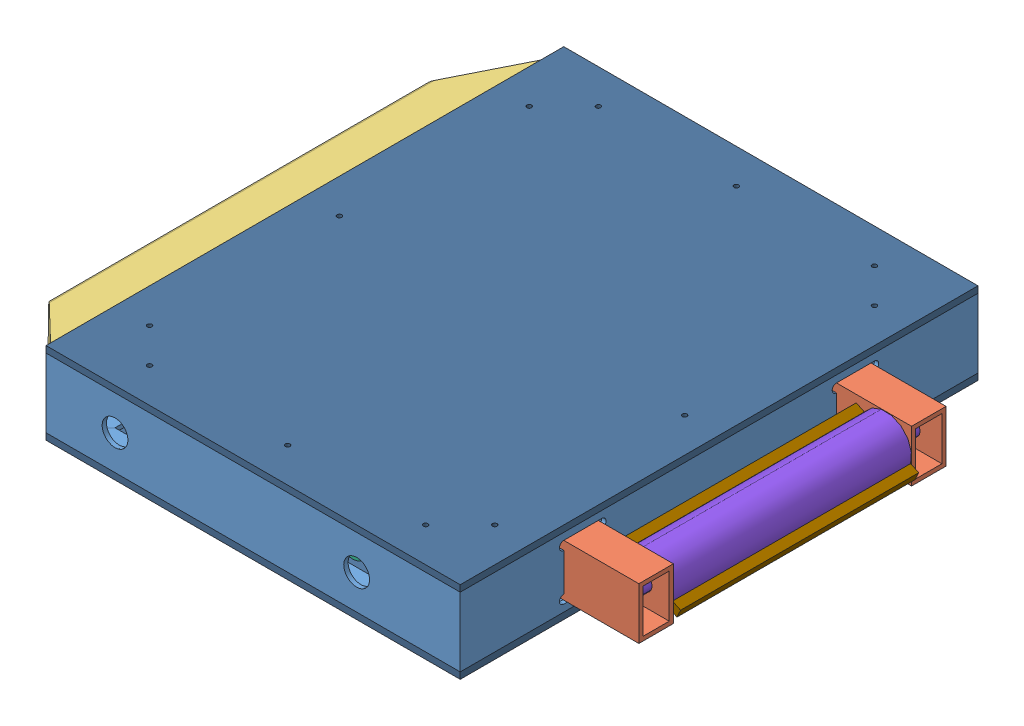
SolidWorks assembly Robot, configuration Default. Lengths in mm.
Overall size (423.92 71.11 381).
28 component instances, 11 part files, 15 mates.
Components (placement in the parent):
- Frame-1: Frame [Default] at (141.475 35.5407 10.1668) size (411.9 66.35 381)
  - Frame C-Channel-1: Frame C-Channel [Front] at (140.3478 189.2176 116.1664) x (0 1 0) z (0 0 1) size (50.8 25.4 381)
  - Frame C-Channel-2: Frame C-Channel [Back] at (-164.4522 189.2176 116.1664) x (0 -1 0) z (0 0 1) size (50.8 25.4 381)
  - Frame C-Channel-3: Frame C-Channel [Side] at (140.3478 189.2176 116.1664) x (0 -1 0) z (-1 0 0) size (50.8 25.4 304.8)
  - Frame C-Channel-4: Frame C-Channel [Side] at (140.3478 189.2176 497.1664) x (0 1 0) z (-1 0 0) size (50.8 25.4 304.8)
  - Roller Arm-1: Roller Arm [Motor] at (-161.2772 189.2176 206.3364) x (1 0 0) z (0 0 -1) size (355.6 38.1 25.4)
  - Roller Arm-2: Roller Arm [Default] at (-161.2772 189.2176 406.9964) size (355.6 38.1 25.4)
  - Rear Bumper-1: Rear Bumper [Default] at (-194.3188 178.4172 306.2947) x (0 0 -1) z (0.896344 -0.44336 0) size (378.57 44.9 57.7)
  - Electronics Tray-1: Electronics Tray [Default] at (-24.7522 181.2801 306.6664) x (0 0 1) z (-1 0 0) size (175.26 15.88 76.2)
  - Cross Brace-1: Cross Brace [Default] at (-18.4022 211.4426 406.9964) x (0 -1 0) z (0 0 -1) size (12.7 12.7 200.66)
  - Cross Brace-2: Cross Brace [Default] at (-18.4022 166.9926 206.3364) x (0 1 0) z (0 0 1) size (12.7 12.7 200.66)
  - Motor-1: Motor [Default] at (-91.4272 189.2176 208.2614) x (0 0 -1) z (1 0 0) size (72.8 24.8 24.8)
  - Motor-2: Motor [Default] at (41.9228 189.2176 405.0714) x (0 0 1) z (-1 0 0) size (72.8 24.8 24.8)
  - Motor-3: Motor [Default] at (41.9228 189.2176 208.2614) x (0 0 -1) z (1 0 0) size (72.8 24.8 24.8)
  - Motor-4: Motor [Default] at (-91.4272 189.2176 405.0714) x (0 0 1) z (-1 0 0) size (72.8 24.8 24.8)
  - Motor Mount-1: Motor Mount [Default] at (-91.4272 189.2176 419.6964) x (-1 0 0) z (0 1 0) size (25.4 3.17 25.4)
  - Motor Mount-2: Motor Mount [Default] at (-91.4272 189.2176 193.6364) x (1 0 0) z (0 1 0) size (25.4 3.17 25.4)
  - Motor Mount-3: Motor Mount [Default] at (41.9228 189.2176 419.6964) x (-1 0 0) z (0 1 0) size (25.4 3.17 25.4)
  - Motor Mount-4: Motor Mount [Default] at (41.9228 189.2176 193.6364) x (1 0 0) z (0 1 0) size (25.4 3.17 25.4)
- Roller-1: Roller [Default] at (283.9196 408.749 422.0577) x (0 0 -1) z (-0.423176 -0.906048 0) size (213.36 50.8 38.1)
  - Roller-1: Roller [Default] at (105.2245 107.6043 152.8123) size (213.36 37.57 38.1)
  - Roller Tooth-1: Roller Tooth [Default] at (105.2245 88.5543 155.9873) x (1 0 0) z (0 1 0) size (175.26 6.35 12.7)
  - Roller Tooth-2: Roller Tooth [Default] at (105.2245 126.6543 149.6373) x (1 0 0) z (0 -1 0) size (175.26 6.35 12.7)
- Armor Plate-1: Armor Plate [Default] at (129.4227 194.5957 316.8332) x (0 0 1) z (-1 0 0) size (381 4.76 304.8)
- Armor Plate-2: Armor Plate [Default] at (129.4227 250.1582 316.8332) x (0 0 1) z (-1 0 0) size (381 4.76 304.8)
- Raspberry Pi-1: Raspberry Pi [Default] at (117.5765 219.9957 375.997) size (65 5 30)
- Motor-1: Motor [Default] at (253.2477 224.7582 214.5782) x (0 0 1) z (-1 0 0) size (72.8 24.8 24.8)
- Motor Mount-1: Motor Mount [Default] at (253.2477 224.7582 229.2032) x (1 0 0) z (0 -1 0) size (25.4 3.17 25.4)
Mates (geometry in assembly coordinates):
- Concentric1: concentric anti-aligned: cylinder of Frame-1/Roller Arm-2 through (316.7477 224.7582 429.8642) axis (0 0 -1) radius 6.35; cylinder of Roller-1/Roller-1 through (316.7477 224.7582 423.5132) axis (0 0 1) radius 6.35
- Coincident1: coincident anti-aligned: plane of Frame-1/Roller Arm-2 through (335.7977 205.7082 404.4632) normal (0 0 -1); plane of Roller-1/Roller-1 through (319.4349 230.5117 404.4632) normal (0 0 1)
- Coincident2: coincident aligned: plane of Frame-1/Frame C-Channel-1 through (281.8227 199.3582 507.3332) normal (1 0 0); plane of Armor Plate-2 through (281.8227 254.9207 126.3332) normal (1 0 0)
- Coincident3: coincident anti-aligned: plane of Frame-1/Frame C-Channel-4 through (-22.9773 250.1582 507.3332) normal (0 1 0); plane of Armor Plate-2 through (129.4227 250.1582 316.8332) normal (0 -1 0)
- Coincident4: coincident aligned: plane of Frame-1/Frame C-Channel-4 through (-22.9773 199.3582 507.3332) normal (0 0 1); plane of Armor Plate-2 through (-22.9773 254.9207 507.3332) normal (0 0 1)
- Coincident5: coincident anti-aligned: plane of Frame-1/Frame C-Channel-4 through (-22.9773 199.3582 481.9332) normal (0 -1 0); plane of Armor Plate-1 through (129.4227 199.3582 316.8332) normal (0 1 0)
- Coincident8: coincident aligned: plane of Frame-1/Frame C-Channel-4 through (-22.9773 199.3582 507.3332) normal (0 0 1); plane of Armor Plate-1 through (-22.9773 199.3582 507.3332) normal (0 0 1)
- Coincident9: coincident aligned: plane of Frame-1/Frame C-Channel-1 through (281.8227 199.3582 507.3332) normal (1 0 0); plane of Armor Plate-1 through (281.8227 199.3582 126.3332) normal (1 0 0)
- Coincident10: coincident anti-aligned: plane of Frame-1/Electronics Tray-1 through (116.7227 219.9957 316.8332) normal (0 1 0); plane of Raspberry Pi-1 through (147.0765 219.9957 363.997) normal (0 -1 0)
- Concentric2: concentric anti-aligned: cylinder of Motor-1 through (253.2477 233.2582 237.3782) axis (0 0 -1) radius 1.5; cylinder of Motor Mount-1 through (253.2477 233.2582 232.3782) axis (0 0 1) radius 1.7
- Concentric3: concentric anti-aligned: cylinder of Motor-1 through (253.2477 216.2582 237.3782) axis (0 0 -1) radius 1.5; cylinder of Motor Mount-1 through (253.2477 216.2582 232.3782) axis (0 0 1) radius 1.7
- Coincident11: coincident anti-aligned: plane of Motor-1 through (253.2477 228.7582 232.3782) normal (0 0 -1); plane of Motor Mount-1 through (253.2477 224.7582 232.3782) normal (0 0 1)
- Concentric4: concentric aligned: cylinder of Frame-1/Roller Arm-1 through (253.2477 233.2582 229.2032) axis (0 0 1) radius 1.7; cylinder of Motor Mount-1 through (253.2477 233.2582 232.3782) axis (0 0 1) radius 1.7
- Concentric5: concentric aligned: cylinder of Frame-1/Roller Arm-1 through (253.2477 216.2582 229.2032) axis (0 0 1) radius 1.7; cylinder of Motor Mount-1 through (253.2477 216.2582 232.3782) axis (0 0 1) radius 1.7
- Coincident12: coincident anti-aligned: plane of Frame-1/Roller Arm-1 through (335.7977 243.8082 229.2032) normal (0 0 1); plane of Motor Mount-1 through (253.2477 224.7582 229.2032) normal (0 0 -1)
